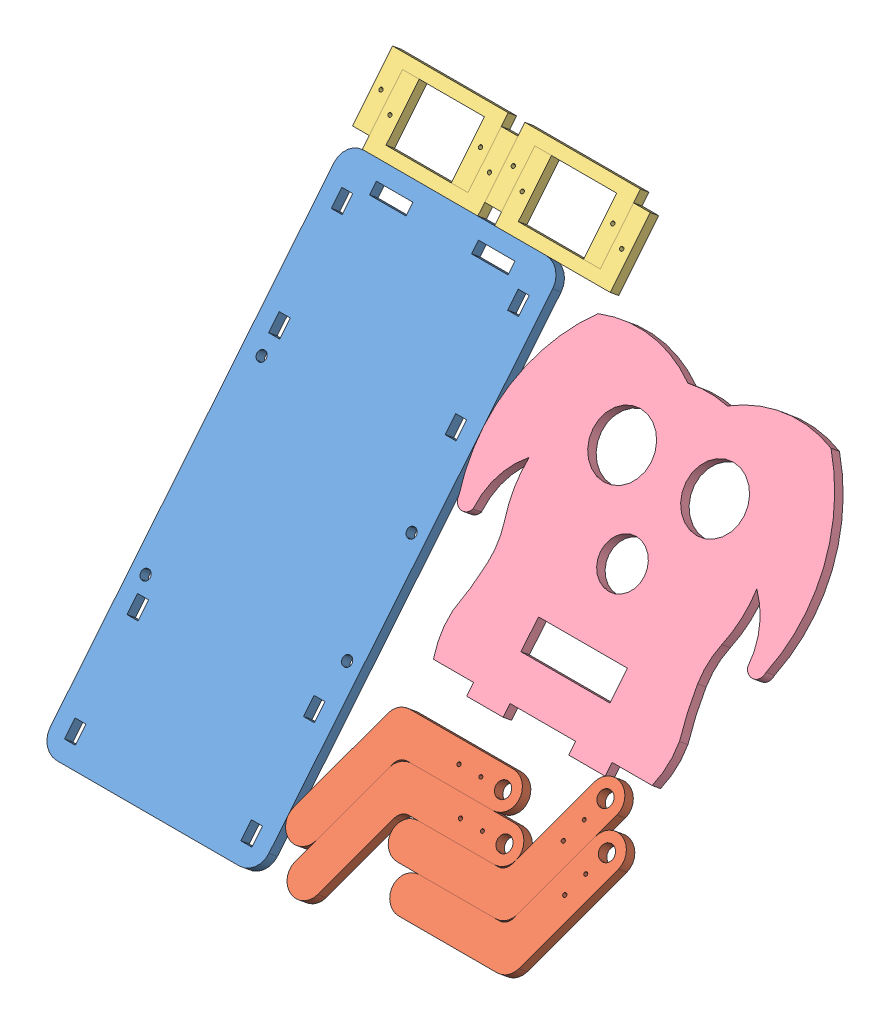
SolidWorks assembly nelo_OLED_laser_cutting, configuration Default. Lengths in mm.
Overall size (150 131.69 110.02).
10 component instances, 4 part files, 31 mates.
Components (placement in the parent):
- Base-1: Base [Default] at (2.0044 259.9739 585.3012) x (1 0 0) z (0 -0.774097 0.633066) size (60 3 133)
- leg-1: leg [Default] at (79.2182 266.4842 583.8525) x (0.369302 0.719376 -0.588315) z (-0.929309 0.285876 -0.233793) size (46.53 3 35.49)
- leg-2: leg [Default] at (117.2177 253.7498 590.3913) x (1 0 0) z (0 -0.774097 0.633066) size (46.53 3 35.49)
- leg-3: leg [Default] at (85.3263 259.5173 589.5501) x (0.369302 0.719376 -0.588315) z (-0.929309 0.285876 -0.233793) size (46.53 3 35.49)
- leg-4: leg [Default] at (111.1097 260.7167 584.6937) x (1 0 0) z (0 -0.774097 0.633066) size (46.53 3 35.49)
- servo_support-5: servo_support [Default] at (38.3044 357.0457 505.9147) x (-1 0 0) z (0 0.633066 0.774097) size (31.7 17.4 3)
- servo_support-6: servo_support [Default] at (2.0044 345.8987 515.0308) x (1 0 0) z (0 0.633066 0.774097) size (31.7 17.4 3)
- servo_support-7: servo_support [Default] at (38.3044 345.8987 515.0308) x (1 0 0) z (0 0.633066 0.774097) size (31.7 17.4 3)
- servo_support-8: servo_support [Default] at (42.9044 358.9449 508.237) x (1 0 0) z (0 -0.633066 -0.774097) size (31.7 17.4 3)
- dog_face_OLED-1: dog_face_OLED [Default] at (65.0617 342.7 517.6468) x (0 -0.774097 0.633066) z (0 0.633066 0.774097) size (79.03 88.48 3)
Mates (geometry in assembly coordinates):
- Coincident2: coincident: plane of Base-1 through (57.0044 246.3911 600.2848) normal (0 0.633066 0.774097); plane of leg-4 through (127.7168 278.9626 573.6475) normal (0 0.633066 0.774097)
- Coincident4: coincident: plane of leg-2 through (133.8248 271.9957 579.3451) normal (0 0.633066 0.774097); plane of leg-4 through (127.7168 278.9626 573.6475) normal (0 0.633066 0.774097)
- Coincident10: coincident: plane of leg-2 through (118.2097 254.9769 593.2633) normal (0 0.774097 -0.633066); plane of leg-4 through (90.1917 254.9769 593.2633) normal (0 -0.774097 0.633066)
- Coincident11: coincident: plane of leg-2 through (129.6429 273.2821 578.293) normal (-0.929309 0.285876 -0.233793); plane of leg-4 through (131.8987 277.6761 574.6996) normal (0.929309 -0.285876 0.233793)
- Coincident14: coincident: plane of leg-1 through (104.9755 267.0115 579.5458) normal (0 -0.774097 0.633066); plane of leg-3 through (111.0836 267.0115 579.5458) normal (0 0.774097 -0.633066)
- Coincident15: coincident: plane of leg-1 through (78.7776 265.5468 580.7436) normal (0.929309 -0.285876 0.233793); plane of leg-3 through (68.4305 245.3913 597.227) normal (-0.929309 0.285876 -0.233793)
- Coincident16: coincident: plane of leg-2 through (133.8248 270.0965 577.0228) normal (0 -0.633066 -0.774097); plane of leg-3 through (111.0836 263.528 582.3946) normal (0 -0.633066 -0.774097)
- Coincident17: coincident: plane of leg-1 through (104.9755 272.3941 579.0193) normal (0 0.633066 0.774097); plane of leg-3 through (111.0836 265.4272 584.7169) normal (0 0.633066 0.774097)
- Coincident18: coincident: plane of leg-3 through (111.0836 260.0446 585.2434) normal (0 -0.774097 0.633066); plane of leg-4 through (112.1016 261.9438 587.5657) normal (0 0.774097 -0.633066)
- Tangent1: tangent: cylinder of leg-3 through (111.0836 263.528 582.3946) axis (0 0.633066 0.774097) radius 4.5; plane of leg-4 through (123.5349 280.249 572.5954) normal (-0.929309 0.285876 -0.233793)
- Parallel1: parallel: plane of Base-1 through (7.0044 242.5206 603.4502) normal (0 -0.774097 0.633066); plane of leg-2 through (96.2997 248.01 598.9609) normal (0 -0.774097 0.633066)
- Tangent2: tangent: plane of Base-1 through (7.0044 242.5206 603.4502) normal (0 -0.774097 0.633066); cylinder of leg-3 through (72.6124 244.1049 598.2791) axis (0 0.633066 0.774097) radius 4.5
- Tangent3: tangent: plane of Base-1 through (62.0044 246.3911 600.2848) normal (1 0 0); cylinder of leg-1 through (66.5044 251.0717 592.5815) axis (0 0.633066 0.774097) radius 4.5
- Distance5: distance = 1 mm: plane of Base-1 through (2.0044 246.3911 600.2848) normal (-1 0 0); line of assembly
- Distance6: distance = 1 mm: plane of Base-1 through (7.0044 242.5206 603.4502) normal (0 -0.774097 0.633066); line of assembly
- Coincident35: coincident: plane of Base-1 through (57.0044 246.3911 600.2848) normal (0 0.633066 0.774097); plane of servo_support-5 through (38.3044 358.9449 508.237) normal (0 0.633066 0.774097)
- Coincident37: coincident: plane of servo_support-5 through (38.3044 358.9449 508.237) normal (0 0.633066 0.774097); plane of servo_support-6 through (2.0044 347.7979 517.3531) normal (0 0.633066 0.774097)
- Coincident38: coincident: plane of servo_support-5 through (33.7044 358.9449 508.237) normal (-1 0 0); plane of servo_support-6 through (33.7044 347.7979 517.3531) normal (1 0 0)
- Coincident39: coincident: plane of servo_support-5 through (33.7044 347.7979 517.3531) normal (0 0.774097 -0.633066); plane of servo_support-6 through (29.1044 347.7979 517.3531) normal (0 -0.774097 0.633066)
- Coincident40: coincident: plane of Base-1 through (7.0044 345.4756 519.2523) normal (0 0.774097 -0.633066); plane of servo_support-5 through (6.6044 345.4756 519.2523) normal (0 -0.774097 0.633066)
- Coincident41: coincident: plane of Base-1 through (2.0044 246.3911 600.2848) normal (-1 0 0); plane of servo_support-6 through (2.0044 361.2672 506.3378) normal (-1 0 0)
- Coincident42: coincident: plane of servo_support-5 through (38.3044 345.4756 519.2523) normal (1 0 0); plane of servo_support-7 through (38.3044 361.2672 506.3378) normal (-1 0 0)
- Coincident43: coincident: plane of Base-1 through (57.0044 246.3911 600.2848) normal (0 0.633066 0.774097); plane of servo_support-7 through (38.3044 347.7979 517.3531) normal (0 0.633066 0.774097)
- Coincident44: coincident: plane of servo_support-6 through (33.7044 361.2672 506.3378) normal (0 0.774097 -0.633066); plane of servo_support-7 through (70.0044 361.2672 506.3378) normal (0 0.774097 -0.633066)
- Coincident45: coincident: plane of Base-1 through (57.0044 246.3911 600.2848) normal (0 0.633066 0.774097); plane of servo_support-8 through (42.9044 358.9449 508.237) normal (0 0.633066 0.774097)
- Coincident47: coincident: plane of Base-1 through (7.0044 345.4756 519.2523) normal (0 0.774097 -0.633066); plane of servo_support-8 through (74.6044 343.5764 516.93) normal (0 -0.774097 0.633066)
- Coincident48: coincident: plane of servo_support-7 through (42.9044 347.7979 517.3531) normal (1 0 0); plane of servo_support-8 through (42.9044 343.5764 516.93) normal (-1 0 0)
- Coincident49: coincident: plane of Base-1 through (57.0044 246.3911 600.2848) normal (0 0.633066 0.774097); plane of dog_face_OLED-1 through (145.4347 310.0187 548.2561) normal (0 0.633066 0.774097)
- Parallel2: parallel: plane of Base-1 through (7.0044 242.5206 603.4502) normal (0 -0.774097 0.633066); plane of dog_face_OLED-1 through (86.6447 284.3452 569.2522) normal (0 -0.774097 0.633066)
- Tangent4: tangent: plane of Base-1 through (62.0044 246.3911 600.2848) normal (1 0 0); cylinder of dog_face_OLED-1 through (106.4027 318.0603 541.6729) axis (0 -0.633066 -0.774097) radius 44.3983
- Coincident51: coincident: cylinder of leg-4 through (127.7168 278.9626 573.6475) axis (0 -0.633066 -0.774097) radius 4.5; line of dog_face_OLED-1 through (125.243 281.8724 571.2678) axis (0 -0.633066 -0.774097)
